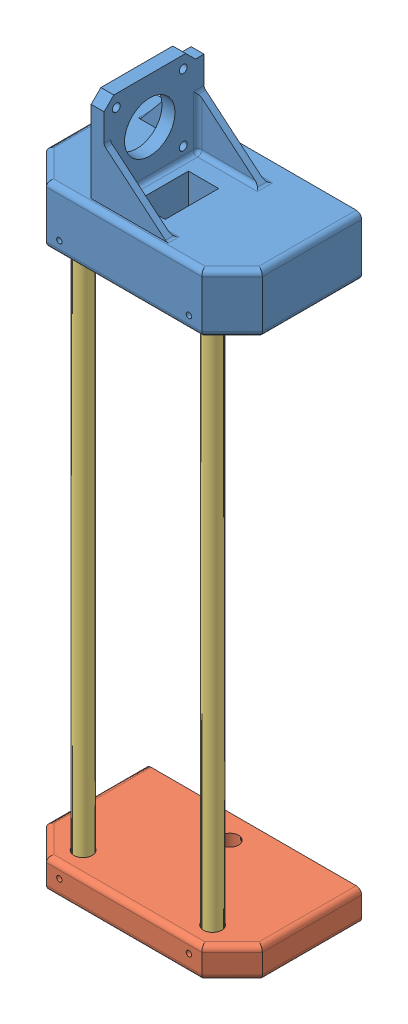
SolidWorks assembly Assem_LinearActuator, configuration Default. Lengths in mm.
Overall size (100 327.3 60).
4 component instances, 3 part files, 9 mates.
Components (placement in the parent):
- Linear actuator_Top holder-1: Linear actuator_Top holder [Default] at (29.3485 49.5221 16.8235) x (1 0 0) z (0 -1 0) size (100 60 69.3)
- Linear actuator_Bottom holder-1: Linear actuator_Bottom holder [Default] at (29.3485 -214.9779 17.8235) x (1 0 0) z (0 1 0) size (100 60 14)
- Linear actuator_Circular guide-1: Linear actuator_Circular guide [Default] at (59.3485 -215.9779 16.8235) x (-0.72491 0 -0.688843) z (0.688843 0 -0.72491) size (8 260 8)
- Linear actuator_Circular guide-2: Linear actuator_Circular guide [Default] at (-0.6515 44.0221 16.8235) x (0.999986 0 0.005294) z (0.005294 0 -0.999986) size (8 260 8)
Mates (geometry in assembly coordinates):
- Concentric1: concentric aligned: cylinder of Linear actuator_Top holder-1 through (-0.6515 36.0221 16.8235) axis (0 1 0) radius 4.25; cylinder of Linear actuator_Circular guide-2 through (-0.6515 -215.9779 16.8235) axis (0 1 0) radius 4
- Concentric5: concentric anti-aligned: cylinder of Linear actuator_Circular guide-1 through (59.3485 55.5221 16.8235) axis (0 -1 0) radius 4; cylinder of ? through (59.3485 -47.9193 16.8235) axis (0 1 0) radius 4
- Concentric6: concentric aligned: cylinder of Linear actuator_Circular guide-2 through (-0.6515 -154.4779 16.8235) axis (0 1 0) radius 4; cylinder of ? through (-0.6515 -47.9193 16.8235) axis (0 1 0) radius 4
- Concentric8: concentric aligned: cylinder of Linear actuator_Bottom holder-1 through (59.3485 -207.9779 16.8235) axis (0 -1 0) radius 4.25; cylinder of Linear actuator_Circular guide-1 through (59.3485 44.0221 16.8235) axis (0 -1 0) radius 4
- Concentric9: concentric anti-aligned: cylinder of Linear actuator_Bottom holder-1 through (-0.6515 -207.9779 16.8235) axis (0 -1 0) radius 4.25; cylinder of Linear actuator_Circular guide-2 through (-0.6515 -215.9779 16.8235) axis (0 1 0) radius 4
- Concentric10: concentric anti-aligned: cylinder of Linear actuator_Top holder-1 through (59.3485 36.0221 16.8235) axis (0 1 0) radius 4.25; cylinder of Linear actuator_Circular guide-1 through (59.3485 44.0221 16.8235) axis (0 -1 0) radius 4
- Coincident6: coincident anti-aligned: plane of Linear actuator_Bottom holder-1 through (59.3485 -215.9779 16.8235) normal (0 1 0); plane of Linear actuator_Circular guide-1 through (59.3485 -215.9779 16.8235) normal (0 -1 0)
- Coincident7: coincident anti-aligned: plane of Linear actuator_Top holder-1 through (-0.6515 44.0221 16.8235) normal (0 -1 0); plane of Linear actuator_Circular guide-2 through (-0.6515 44.0221 16.8235) normal (0 1 0)
- Coincident8: coincident anti-aligned: plane of Linear actuator_Top holder-1 through (59.3485 44.0221 16.8235) normal (0 -1 0); plane of Linear actuator_Circular guide-1 through (59.3485 44.0221 16.8235) normal (0 1 0)
